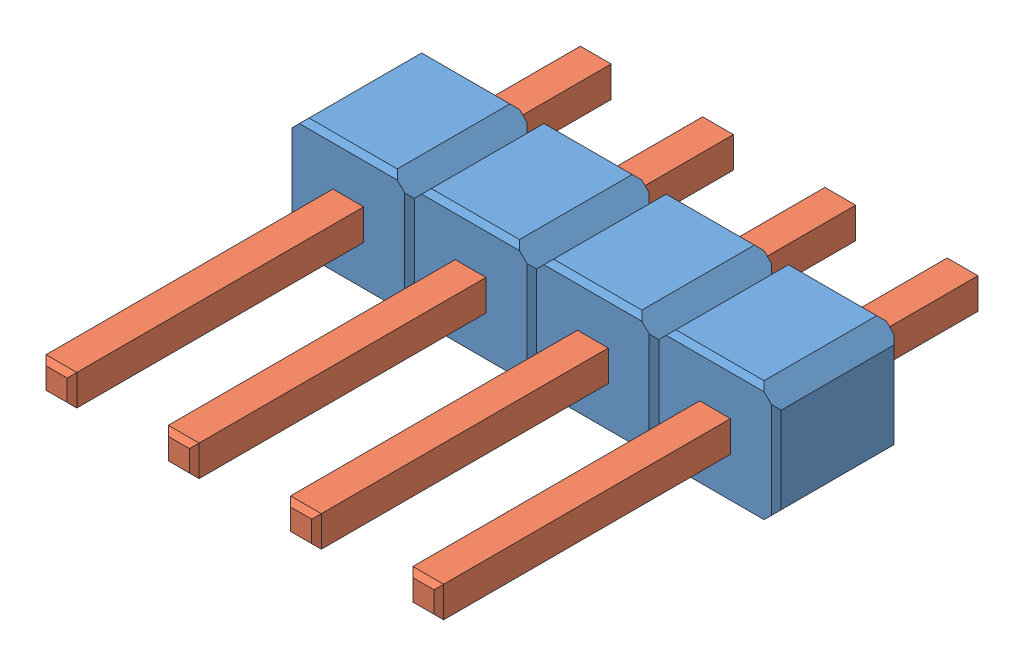
SolidWorks assembly pls_1x4_vert, configuration Default. Lengths in mm.
Overall size (10.16 2.5 11.3).
12 component instances, 2 part files, 6 mates.
Components (placement in the parent):
- pls_1_vert-1: pls_1_vert [Default] at (2.4589 -1.2488 -2.1291) size (2.54 2.5 11.3)
  - pin_plastic-1: pin_plastic [По умолчанию] at (1.6831 0.6372 -1.2507) size (2.54 2.5 2.54)
  - pin-1: pin [Default] at (-0.8569 0.6372 7.3493) x (1 0 0) z (0 1 0) size (0.64 11.3 0.64)
- pls_1_vert-2: pls_1_vert [Default] at (-0.0811 -1.2488 -2.1291) size (2.54 2.5 11.3)
  - pin_plastic-1: pin_plastic [По умолчанию] at (1.6831 0.6372 -1.2507) size (2.54 2.5 2.54)
  - pin-1: pin [Default] at (-0.8569 0.6372 7.3493) x (1 0 0) z (0 1 0) size (0.64 11.3 0.64)
- pls_1_vert-4: pls_1_vert [Default] at (-2.6211 -1.2488 -2.1291) size (2.54 2.5 11.3)
  - pin_plastic-1: pin_plastic [По умолчанию] at (1.6831 0.6372 -1.2507) size (2.54 2.5 2.54)
  - pin-1: pin [Default] at (-0.8569 0.6372 7.3493) x (1 0 0) z (0 1 0) size (0.64 11.3 0.64)
- pls_1_vert-5: pls_1_vert [Default] at (-5.1611 -1.2488 -2.1291) size (2.54 2.5 11.3)
  - pin_plastic-1: pin_plastic [По умолчанию] at (1.6831 0.6372 -1.2507) size (2.54 2.5 2.54)
  - pin-1: pin [Default] at (-0.8569 0.6372 7.3493) x (1 0 0) z (0 1 0) size (0.64 11.3 0.64)
Mates (geometry in assembly coordinates):
- Совпадение1: coincident anti-aligned: line of pls_1_vert-1/pin_plastic-1 through (0.332 -1.5081 -0.9398) axis (0 1 0); line of pls_1_vert-2/pin_plastic-1 through (0.332 0.2848 -0.9398) axis (0 -1 0)
- Совпадение2: coincident aligned: line of pls_1_vert-1/pin_plastic-1 through (0.332 0.2848 -0.9398) axis (0 0 -1); line of pls_1_vert-2/pin_plastic-1 through (0.332 0.2848 -0.9398) axis (0 0 -1)
- Совпадение3: coincident anti-aligned: line of pls_1_vert-2/pin_plastic-1 through (-2.208 -1.5081 -0.9398) axis (0 1 0); line of pls_1_vert-4/pin_plastic-1 through (-2.208 0.2848 -0.9398) axis (0 -1 0)
- Совпадение4: coincident aligned: line of pls_1_vert-2/pin_plastic-1 through (-2.208 0.2848 -0.9398) axis (0 0 -1); line of pls_1_vert-4/pin_plastic-1 through (-2.208 0.2848 -0.9398) axis (0 0 -1)
- Совпадение5: coincident anti-aligned: line of pls_1_vert-4/pin_plastic-1 through (-4.748 -1.5081 -0.9398) axis (0 1 0); line of pls_1_vert-5/pin_plastic-1 through (-4.748 0.2848 -0.9398) axis (0 -1 0)
- Совпадение6: coincident aligned: line of pls_1_vert-4/pin_plastic-1 through (-4.748 0.2848 -0.9398) axis (0 0 -1); line of pls_1_vert-5/pin_plastic-1 through (-4.748 0.2848 -0.9398) axis (0 0 -1)
